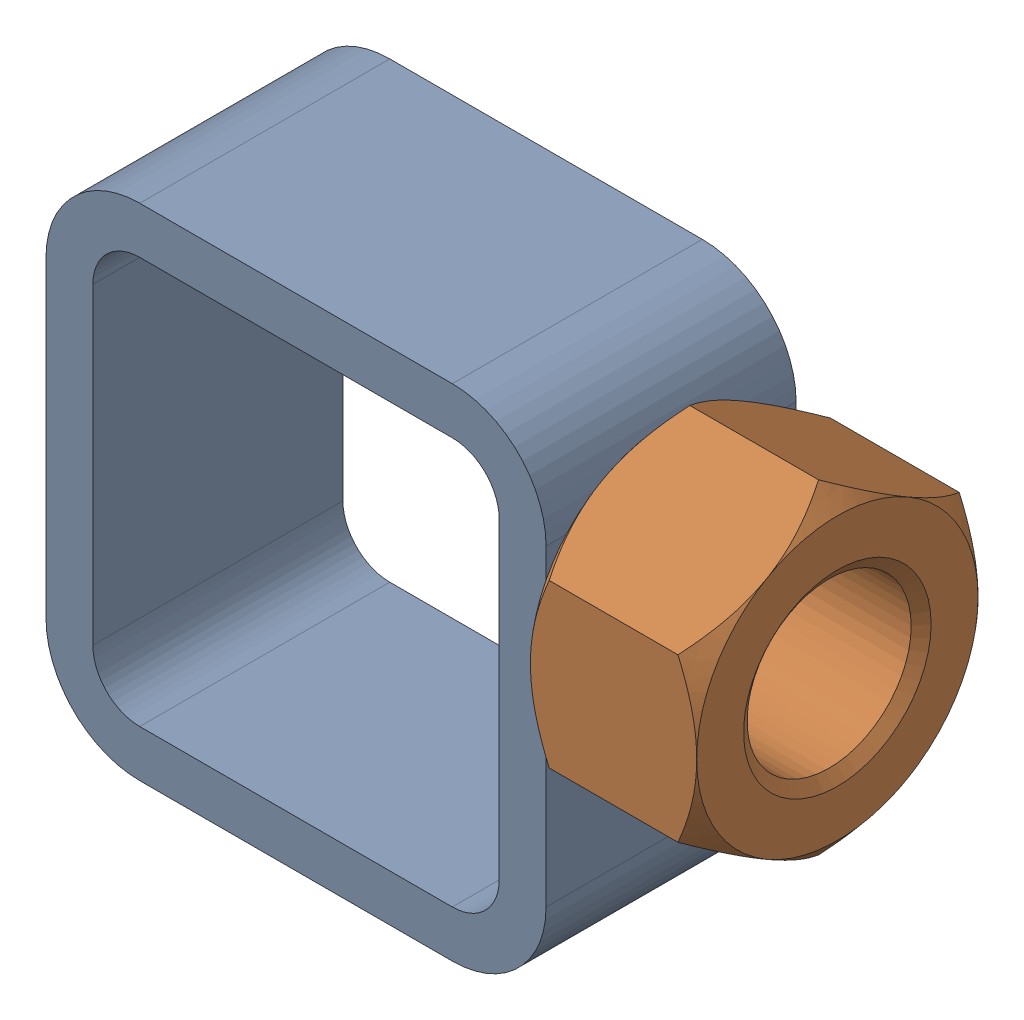
SolidWorks assembly 01-005-00-0-7, configuration Default. Lengths in mm.
Overall size (67.69 50.8 28.57).
2 component instances, 2 part files, 0 mates.
Components (placement in the parent):
- tube square_ai(PreviewCfg)-1: tube square_ai(PreviewCfg) [Default] at origin size (50.8 50.8 25.4)
- hex nut_ai(HNUT 0.7500-10-D-C)-1: hex nut_ai(HNUT 0.7500-10-D-C) [Default] at (67.691 31.75 0) x (0 0 -1) z (1 0 0) size (28.57 33 16.89)
